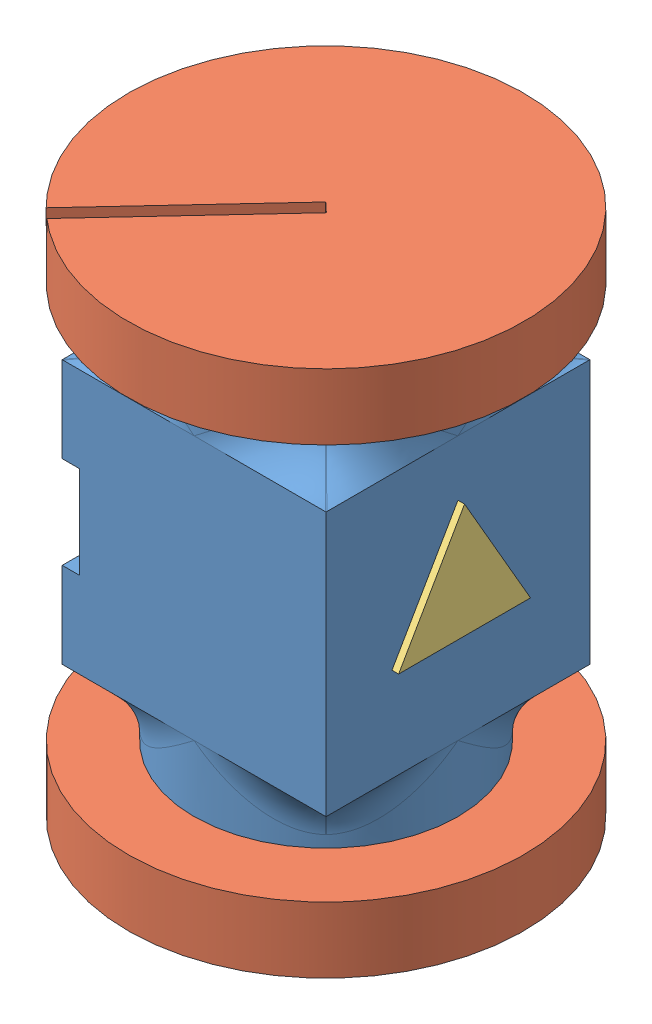
SolidWorks assembly Assem1, configuration Default. Lengths in mm.
Overall size (107.69 101.6 107.69).
4 component instances, 3 part files, 4 mates.
Components (placement in the parent):
- Main Body-1: Main Body [Default] at (36.5496 38.0961 55.3465) size (50.8 76.2 50.8)
- Cap-1: Cap [Default] at (36.5496 76.1961 55.3465) x (-0.732125 0 -0.68117) z (0.68117 0 -0.732125) size (76.2 12.7 76.2)
- Triangular Sticker-1: Triangular Sticker [Default] at (61.9496 30.7638 68.0465) x (0 0 -1) z (0 -1 0) size (25.4 1.27 22)
- Cap-2: Cap [Default] at (36.5496 -0.0039 55.3465) x (-0.621952 0 0.783056) z (0.783056 0 0.621952) size (76.2 12.7 76.2)
Mates (geometry in assembly coordinates):
- Coincident1: coincident anti-aligned: plane of Main Body-1 through (36.5496 76.1961 55.3465) normal (0 1 0); plane of Cap-1 through (36.5496 76.1961 55.3465) normal (0 -1 0)
- Concentric1: concentric aligned: circle of Main Body-1; circle of Cap-1
- ProfileCenter1: profile center anti-aligned: plane of Cap-2 through (36.5496 -0.0039 55.3465) normal (0 1 0); plane of Main Body-1 through (36.5496 -0.0039 55.3465) normal (0 -1 0)
- ProfileCenter3: profile center anti-aligned: plane of Triangular Sticker-1 through (61.9496 30.7638 68.0465) normal (-1 0 0); plane of Main Body-1 through (61.9496 63.4961 80.7465) normal (1 0 0)
